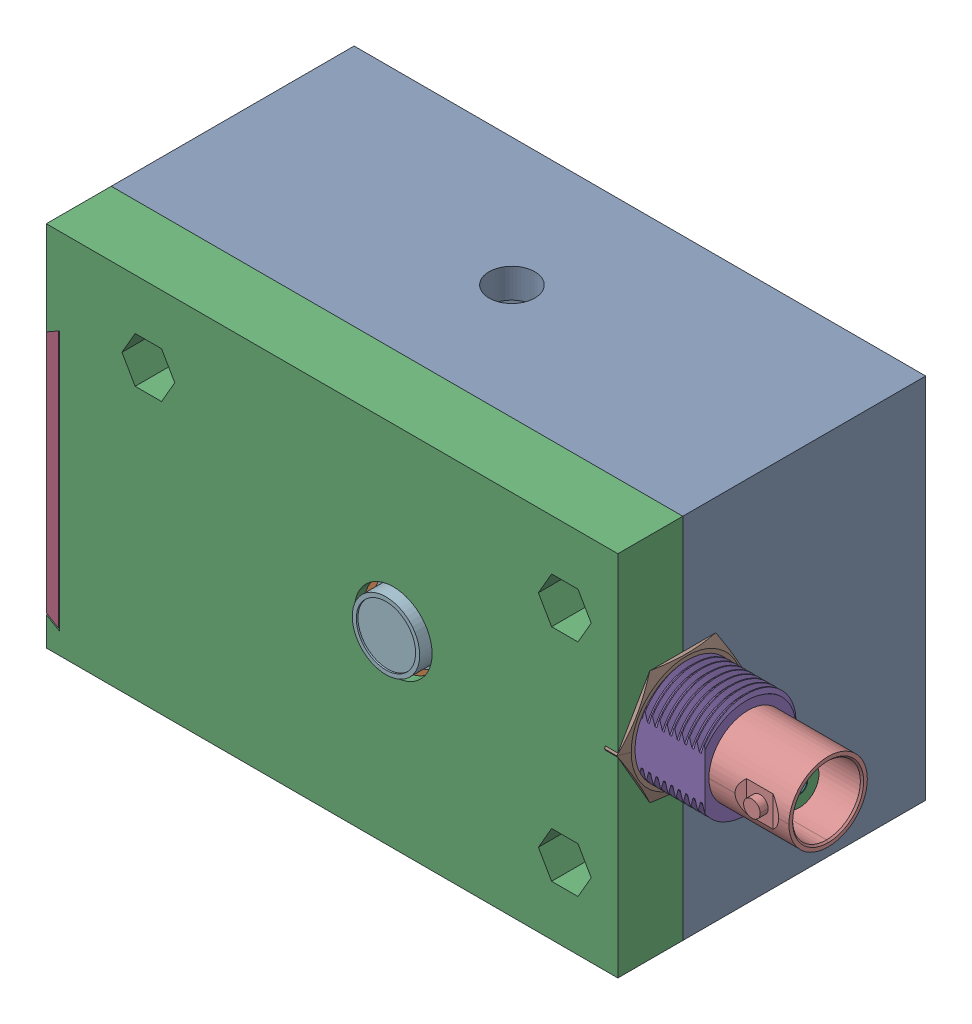
SolidWorks assembly Photodetector Assembly, configuration Default. Lengths in mm.
Overall size (87.8 45 38.6).
9 component instances, 8 part files, 14 mates.
Components (placement in the parent):
- Printed Base-1: Printed Base [Default] at origin size (70 45 29.75)
- PCB Assembly-1: PCB Assembly [Default] at (0 0 21.9) x (-1 0 0) z (0 0 1) size (85.3 35 19.9)
  - PCB Base-1: PCB Base [Default] at origin size (65 35 1.6)
  - BNC Connector-1: BNC Connector [Default] at (-23.42 -1.125 1.04) x (0 -1 0) z (-1 0 0) size (16.19 19.14 35.2)
  - MT-03 Photodetector-1: MT-03 Photodetector [Default] at (-7.5 -0.5 12.6) x (-1 0 0) z (0 0 -1) size (9.2 9.2 17.1)
- 9V-battery-1: 9V-battery [Default] at (-69.1046 -26.4834 2.955) x (0 -1 0) z (0 0 1) size (26.04 47.88 17.14)
- PCB Insulation-1: PCB Insulation [Default] at (0 0 20.1) x (-1 0 0) z (0 0 1) size (65 35 1.8)
- Lid-1: Lid [Default] at (0 0 36.5) size (70 45 14.2)
- Battery Cap-1: Battery Cap [Default] at (-35 -3.88 37.7) x (0 1 0) z (0 0 -1) size (31.53 1.5 36.1)
Mates (geometry in assembly coordinates):
- Coincident10: coincident anti-aligned: plane of Printed Base-1 through (28.5 -13.5 20.1) normal (0 0 1); plane of PCB Insulation-1 through (0 0 20.1) normal (0 0 -1)
- Concentric12: concentric aligned: cylinder of Printed Base-1 through (28.5 -13.5 18.1) axis (0 0 -1) radius 4.25; cylinder of PCB Insulation-1 through (28.5 -13.5 21.9) axis (0 0 -1) radius 3.25
- Parallel3: parallel anti-aligned: plane of Printed Base-1 through (-35 -22.5 1.6) normal (0 -1 0); plane of PCB Insulation-1 through (32.5 17.5 20.4) normal (0 1 0)
- Coincident13: coincident anti-aligned: plane of PCB Assembly-1/PCB Base-1 through (0 0 21.9) normal (0 0 -1); plane of PCB Insulation-1 through (28.5 -13.5 21.9) normal (0 0 1)
- Concentric13: concentric aligned: cylinder of PCB Assembly-1/PCB Base-1 through (28.5 -13.5 21.9) axis (0 0 1) radius 1.75; cylinder of PCB Insulation-1 through (28.5 -13.5 18.8) axis (0 0 1) radius 1.75
- Parallel4: parallel aligned: plane of PCB Assembly-1/PCB Base-1 through (32.5 -17.5 23.5) normal (0 -1 0); plane of PCB Insulation-1 through (32.5 -17.5 20.4) normal (0 -1 0)
- Coincident15: coincident anti-aligned: plane of 9V-battery-1 through (-0.6444 -6.3825 20.1) normal (0 0 1); plane of PCB Insulation-1 through (0 0 20.1) normal (0 0 -1)
- Distance2: distance = 1.5 mm anti-aligned: plane of Printed Base-1 through (-33.4 -20.9 29.75) normal (0 1 0); plane of 9V-battery-1 through (-0.6444 -19.4 11.705) normal (0 -1 0)
- Coincident18: coincident anti-aligned: plane of PCB Assembly-1/PCB Base-1 through (0 0 23.5) normal (0 0 1); plane of Lid-1 through (28.5 -13.5 23.5) normal (0 0 -1)
- Concentric15: concentric aligned: cylinder of PCB Assembly-1/PCB Base-1 through (-22.5 13.5 21.9) axis (0 0 1) radius 1.75; cylinder of Lid-1 through (-22.5 13.5 23.5) axis (0 0 1) radius 1.75
- Coincident20: coincident aligned: plane of Printed Base-1 through (-35 22.5 1.6) normal (-1 0 0); plane of Lid-1 through (-35 22.5 37.7) normal (-1 0 0)
- Coincident21: coincident aligned: plane of Printed Base-1 through (-35 22.5 1.6) normal (-1 0 0); plane of Battery Cap-1 through (-35 -18.78 1.6) normal (-1 0 0)
- Coincident22: coincident anti-aligned: plane of Printed Base-1 through (0 0 1.6) normal (0 0 1); plane of Battery Cap-1 through (-35 -3.88 1.6) normal (0 0 -1)
- Coincident23: coincident anti-aligned: plane of Lid-1 through (-35 11.02 27.7) normal (0.5 -0.866025 0); plane of Battery Cap-1 through (-35 11.02 1.6) normal (-0.5 0.866025 0)
